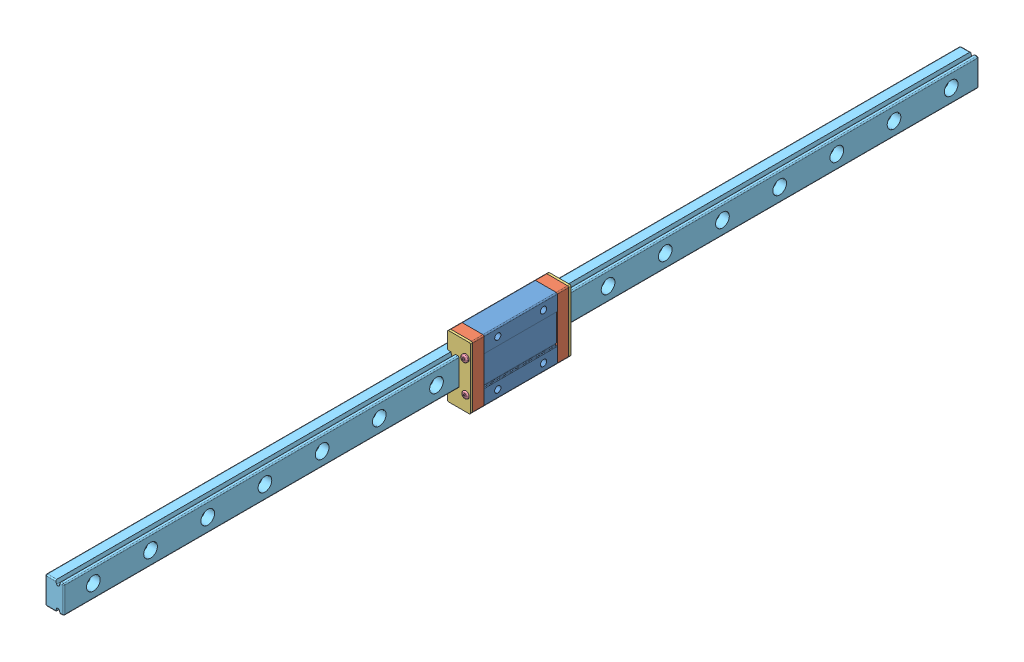
SolidWorks assembly Assem1, configuration Default. Lengths in mm.
Overall size (13 27 400).
10 component instances, 5 part files, 26 mates.
Components (placement in the parent):
- Main Block-1: Main Block [Default] at (169.1827 226.6144 359.262) x (0 0 1) z (1 0 0) size (32 27 10)
- Green End Cap-1: Green End Cap [Default] at (174.1827 226.6144 343.262) x (0 1 0) z (0 0 -1) size (27 10 5)
- Red End Cap-1: Red End Cap [Default] at (174.1827 226.6144 338.262) x (0 1 0) z (0 0 -1) size (27 10 1)
- Green End Cap-2: Green End Cap [Default] at (174.1827 226.6144 375.262) x (0 -1 0) z (0 0 1) size (27 10 5)
- Red End Cap-2: Red End Cap [Default] at (174.1827 226.6144 380.262) x (0 -1 0) z (0 0 1) size (27 10 1)
- Button M3x8-1: Button M3x8 [Default] at (177.1827 219.6144 381.762) x (0.381849 -0.924225 0) z (0 0 -1) size (3 3 7)
- Button M3x8-2: Button M3x8 [Default] at (177.1827 233.6144 382.262) x (0.381849 -0.924225 0) z (0 0 -1) size (3 3 7)
- Button M3x8-3: Button M3x8 [Default] at (177.1827 219.6144 336.762) x (-0.381849 0.924225 0) z (0 0 1) size (3 3 7)
- Button M3x8-5: Button M3x8 [Default] at (177.1827 233.6144 336.762) x (-0.381849 0.924225 0) z (0 0 1) size (3 3 7)
- Rail 400mm-3: Rail 400mm [Default] at (170.1827 226.6144 554.048) x (0 0 -1) z (1 0 0) size (400 12 8)
Mates (geometry in assembly coordinates):
- Coincident1: coincident: plane of ? through (405.2255 225.8015 379.5515) normal (0 0 1); plane of Main Block-1
- Coincident2: coincident: plane of ? through (405.2255 225.8015 379.5515) normal (0 1 0); plane of Main Block-1
- Coincident3: coincident: plane of Main Block-1 through (179.1827 213.1144 343.262) normal (0 0 -1); plane of Green End Cap-1 through (174.1827 226.6144 343.262) normal (0 0 1)
- Coincident4: coincident: plane of Main Block-1 through (179.1827 240.1144 343.262) normal (0 1 0); plane of Green End Cap-1 through (179.1827 240.1144 338.262) normal (0 1 0)
- Coincident5: coincident: plane of Main Block-1 through (169.1827 226.6144 359.262) normal (-1 0 0); plane of Green End Cap-1 through (169.1827 232.6144 338.262) normal (-1 0 0)
- Coincident9: coincident: plane of Main Block-1 through (179.1827 213.1144 375.262) normal (0 0 1); plane of Green End Cap-2 through (174.1827 226.6144 375.262) normal (0 0 -1)
- Coincident10: coincident: plane of Main Block-1 through (179.1827 240.1144 343.262) normal (0 1 0); plane of Green End Cap-2 through (179.1827 240.1144 380.262) normal (0 1 0)
- Coincident11: coincident: plane of Main Block-1 through (179.1827 226.6144 359.262) normal (1 0 0); plane of Green End Cap-2 through (179.1827 240.1144 380.262) normal (1 0 0)
- Coincident12: coincident: plane of Green End Cap-2 through (174.1827 226.6144 380.262) normal (0 0 1); plane of Red End Cap-2 through (174.1827 226.6144 380.262) normal (0 0 -1)
- Coincident13: coincident: plane of Green End Cap-2 through (179.1827 240.1144 380.262) normal (0 1 0); plane of Red End Cap-2 through (179.1827 240.1144 381.262) normal (0 1 0)
- Coincident14: coincident: plane of Green End Cap-2 through (179.1827 240.1144 380.262) normal (1 0 0); plane of Red End Cap-2 through (179.1827 240.1144 381.262) normal (1 0 0)
- Coincident16: coincident: plane of Green End Cap-1 through (174.1827 226.6144 338.262) normal (0 0 -1); plane of Red End Cap-1 through (174.1827 226.6144 338.262) normal (0 0 1)
- Coincident17: coincident: plane of Green End Cap-1 through (179.1827 213.1144 338.262) normal (0 -1 0); plane of Red End Cap-1 through (179.1827 213.1144 337.262) normal (0 -1 0)
- Coincident18: coincident: plane of Green End Cap-1 through (169.1827 213.1144 338.262) normal (-1 0 0); plane of Red End Cap-1 through (169.1827 213.1144 337.262) normal (-1 0 0)
- Concentric1: concentric: cylinder of Green End Cap-1 through (177.1827 219.6144 343.262) axis (0 0 -1) radius 1; cylinder of Button M3x8-3 through (177.1827 219.6144 343.762) axis (0 0 -1) radius 1
- Coincident19: coincident: plane of Red End Cap-1 through (177.1827 219.6144 337.762) normal (0 0 -1); plane of Button M3x8-3 through (177.1827 219.6144 337.762) normal (0 0 1)
- Concentric2: concentric: cylinder of Green End Cap-1 through (177.1827 233.6144 343.262) axis (0 0 -1) radius 1; cylinder of Button M3x8-5 through (177.1827 233.6144 343.762) axis (0 0 -1) radius 1
- Coincident20: coincident: plane of Red End Cap-1 through (177.1827 233.6144 337.762) normal (0 0 -1); plane of Button M3x8-5 through (177.1827 233.6144 337.762) normal (0 0 1)
- Concentric3: concentric: cylinder of Green End Cap-2 through (177.1827 219.6144 375.262) axis (0 0 1) radius 1; cylinder of Button M3x8-1 through (177.1827 219.6144 374.762) axis (0 0 1) radius 1
- Coincident21: coincident: plane of Red End Cap-2 through (177.1827 219.6144 380.762) normal (0 0 1); plane of Button M3x8-1 through (177.1827 219.6144 380.762) normal (0 0 -1)
- Concentric4: concentric: cylinder of Green End Cap-2 through (177.1827 233.6144 375.262) axis (0 0 1) radius 1; cylinder of Button M3x8-2 through (177.1827 233.6144 375.262) axis (0 0 1) radius 1
- Coincident22: coincident: plane of Red End Cap-2 through (174.1827 226.6144 381.262) normal (0 0 1); plane of Button M3x8-2 through (177.1827 233.6144 381.262) normal (0 0 -1)
- Coincident24: coincident: plane of Main Block-1; plane of ? through (166.1827 232.5585 379.9218) normal (-1 0 0)
- Coincident25: coincident: plane of Main Block-1; plane of ? through (166.1827 220.5585 379.9218) normal (0 -1 0)
- Coincident27: coincident: plane of Main Block-1 through (174.1827 220.6144 380.262) normal (-1 0 0); plane of Rail 400mm-3 through (174.1827 232.6144 154.048) normal (1 0 0)
- Coincident28: coincident: plane of Main Block-1 through (172.6827 232.6144 380.262) normal (0 -1 0); plane of Rail 400mm-3 through (174.1827 232.6144 154.048) normal (0 1 0)
